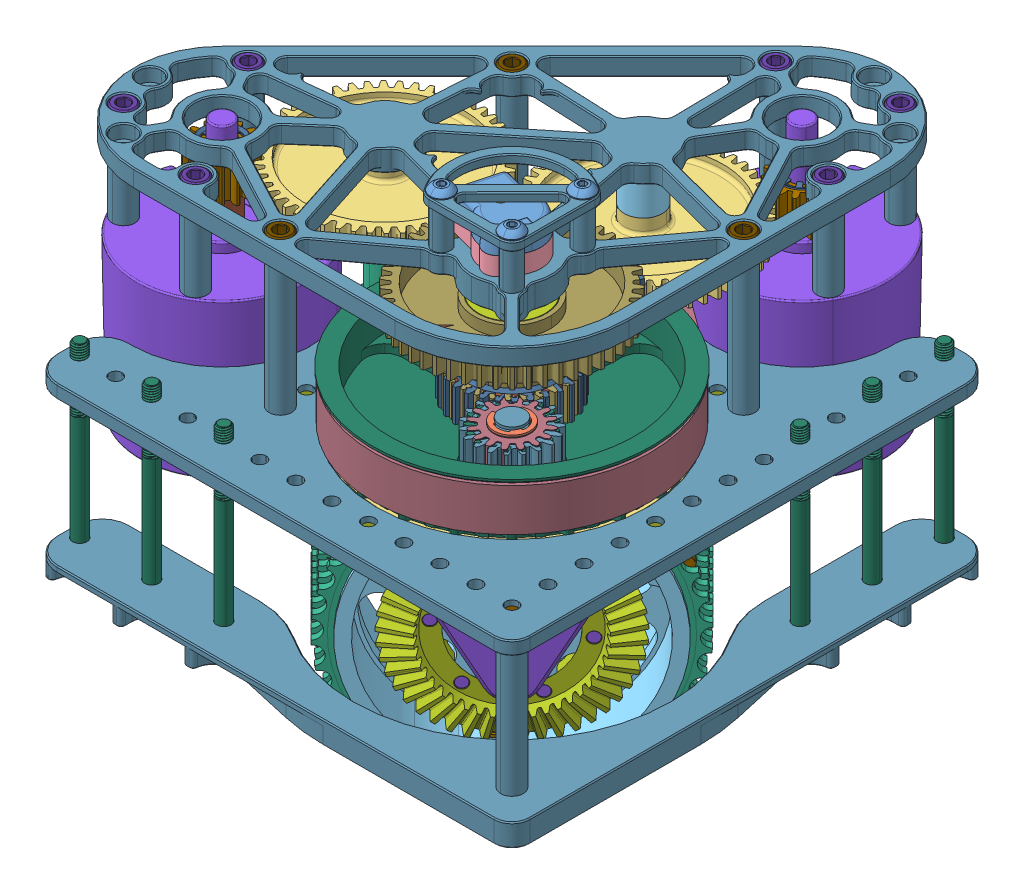
SolidWorks assembly SDS MK4i Swerve Module, 10-32, NEOs.STEP, configuration Default. Lengths in mm.
Overall size (225.17 192.31 225.17).
101 component instances, 51 part files, 0 mates.
Components (placement in the parent):
- CANcoder Assembly.STEP-1: CANcoder Assembly.STEP [Default] at (-66.675 132.3975 -66.675) x (-0.260871 0 0.965374) z (0 1 0) size (21.75 26.91 13.52)
  - CANcoder Top Housing.STEP-1: CANcoder Top Housing.STEP [Default] at origin size (21.53 26.79 8.94)
  - CANcoder PCA.STEP-1: CANcoder PCA.STEP [Default] at (0 0 22.3055) size (15.93 23.27 3.19)
  - CANcoder Screw.STEP-1: CANcoder Screw.STEP [Default] at origin size (4.24 4.24 12.65)
  - CANcoder Bottom Housing.STEP-1: CANcoder Bottom Housing.STEP [Default] at origin size (21.75 26.91 6.35)
- MK4 Turret Assembly_Billet Wheel.STEP-1: MK4 Turret Assembly_Billet Wheel.STEP [Default] at (-66.675 0 -66.675) x (-0.707107 0 0.707107) z (-0.707107 0 -0.707107) size (140.36 172.84 120.2)
  - MK4 Billet Wheel Assembly.STEP-1: MK4 Billet Wheel Assembly.STEP [Default] at (0 50.7435 0.0635) x (0 0 -1) z (-0.607274 0.794493 0) size (42.38 100.13 100.13)
    - Wheel, SDS, Nitrile Tread, 4in X 1.5in, Bearing Bore.STEP-1: Wheel, SDS, Nitrile Tread, 4in X 1.5in, Bearing Bore.STEP [Default] at origin size (42.28 88.9 88.9)
    - Tread, Blue Nitrile 4in X 1.5in.STEP-1: Tread, Blue Nitrile 4in X 1.5in.STEP [Default] at origin size (38.1 100.13 100.13)
    - Bevel Gear, 4515.STEP-1: Bevel Gear, 4515.STEP [Default] at (16.8297 0 0) x (0 -1 0) z (0 0 1) size (68.38 7.77 68.42)
    - Screw, 10-32 X .75, Button, 91255A269_91255A269.STEP-1: Screw, 10-32 X .75, Button, 91255A269_91255A269.STEP [Default] at (-4.826 0 20.6375) x (0 -0.847203 -0.531269) z (-1 0 0) size (9.17 9.17 21.62)
    - Screw, 10-32 X .75, Button, 91255A269_91255A269.STEP-2: Screw, 10-32 X .75, Button, 91255A269_91255A269.STEP [Default] at (-4.826 -17.8726 10.3187) x (0 -0.99925 -0.038711) z (-1 0 0) size (9.17 9.17 21.62)
    - Screw, 10-32 X .75, Button, 91255A269_91255A269.STEP-3: Screw, 10-32 X .75, Button, 91255A269_91255A269.STEP [Default] at (-4.826 -17.8726 -10.3187) x (0 -0.986188 -0.165633) z (-1 0 0) size (9.17 9.17 21.62)
    - Screw, 10-32 X .75, Button, 91255A269_91255A269.STEP-4: Screw, 10-32 X .75, Button, 91255A269_91255A269.STEP [Default] at (-4.826 0 -20.6375) x (0 -0.966455 -0.256836) z (-1 0 0) size (9.17 9.17 21.62)
    - Screw, 10-32 X .75, Button, 91255A269_91255A269.STEP-5: Screw, 10-32 X .75, Button, 91255A269_91255A269.STEP [Default] at (-4.826 17.8726 -10.3187) x (0 -0.95104 -0.309068) z (-1 0 0) size (9.17 9.17 21.62)
    - Screw, 10-32 X .75, Button, 91255A269_91255A269.STEP-6: Screw, 10-32 X .75, Button, 91255A269_91255A269.STEP [Default] at (-4.826 17.8726 10.3187) x (0 -0.947988 -0.318305) z (-1 0 0) size (9.17 9.17 21.62)
    - Screw, 10-32 X .5, Button, 97763A232_97763A232.STEP-1: Screw, 10-32 X .5, Button, 97763A232_97763A232.STEP [Default] at (11.1125 -40.6604 7.1695) x (-0.785325 0.107503 0.609678) z (0 -0.984808 0.173648) size (9.17 9.17 15.27)
    - Screw, 10-32 X .5, Button, 97763A232_97763A232.STEP-2: Screw, 10-32 X .5, Button, 97763A232_97763A232.STEP [Default] at (-11.1125 -40.6604 7.1695) x (-0.636812 0.133886 0.759306) z (0 -0.984808 0.173648) size (9.17 9.17 15.27)
    - Screw, 10-32 X .5, Button, 97763A232_97763A232.STEP-3: Screw, 10-32 X .5, Button, 97763A232_97763A232.STEP [Default] at (-11.1125 -40.6604 -7.1695) x (0.726076 -0.119403 0.677168) z (0 -0.984808 -0.173648) size (9.17 9.17 15.27)
    - Screw, 10-32 X .5, Button, 97763A232_97763A232.STEP-4: Screw, 10-32 X .5, Button, 97763A232_97763A232.STEP [Default] at (11.1125 -40.6604 -7.1695) x (0.841108 -0.09392 0.53265) z (0 -0.984808 -0.173648) size (9.17 9.17 15.27)
    - Screw, 10-32 X .5, Button, 97763A232_97763A232.STEP-5: Screw, 10-32 X .5, Button, 97763A232_97763A232.STEP [Default] at (-11.1125 20.6438 -35.7562) x (0.804058 -0.514897 -0.297276) z (0 0.5 -0.866025) size (9.17 9.17 15.27)
    - Screw, 10-32 X .5, Button, 97763A232_97763A232.STEP-6: Screw, 10-32 X .5, Button, 97763A232_97763A232.STEP [Default] at (11.1125 20.6438 -35.7562) x (0.926716 -0.32542 -0.187881) z (0 0.5 -0.866025) size (9.17 9.17 15.27)
    - Screw, 10-32 X .5, Button, 97763A232_97763A232.STEP-7: Screw, 10-32 X .5, Button, 97763A232_97763A232.STEP [Default] at (11.1125 20.6438 35.7562) x (0.200031 0.848523 -0.489895) z (0 0.5 0.866025) size (9.17 9.17 15.27)
    - Screw, 10-32 X .5, Button, 97763A232_97763A232.STEP-8: Screw, 10-32 X .5, Button, 97763A232_97763A232.STEP [Default] at (-11.1125 20.6438 35.7562) x (0.515054 0.74232 -0.428579) z (0 0.5 0.866025) size (9.17 9.17 15.27)
  - Double Gear, 20DP, 28T, 50T.STEP-1: Double Gear, 20DP, 28T, 50T.STEP [Default] at (0 110.1225 0) x (-0.730582 0 -0.682825) z (0 1 0) size (65.97 66.04 34.49)
  - Double Gear, 20DP, 25T, 50T.STEP-1: Double Gear, 20DP, 25T, 50T.STEP [Default] at (0 110.1225 0) x (-0.730582 0 -0.682825) z (0 1 0) size (65.97 66.04 34.49)
  - Double Gear, 20DP, 27T, 50T.STEP-1: Double Gear, 20DP, 27T, 50T.STEP [Default] at (0 110.1225 0) x (-0.730582 0 -0.682825) z (0 1 0) size (65.97 66.04 34.49)
  - Gear, 20DP, 16T, .375Hex, 217-5451.STEP-1: Gear, 20DP, 16T, .375Hex, 217-5451.STEP [Default] at (0 115.2978 -28.0162) x (-0.717682 0 -0.696371) z (0 -1 0) size (22.6 22.6 12.6)
  - Gear, 19T, 20DP, .375Hex.STEP-1: Gear, 19T, 20DP, .375Hex.STEP [Default] at (0 115.2978 -28.0162) x (-0.696371 0 0.717682) z (-0.717682 0 -0.696371) size (26.55 12.6 26.64)
  - Gear, 17T, 20DP, .375Hex.STEP-1: Gear, 17T, 20DP, .375Hex.STEP [Default] at (0 115.2978 -28.0162) x (0 1 0) z (-0.696371 0 0.717682) size (12.6 23.99 24.09)
  - Bevel Gear, 1545.STEP-1: Bevel Gear, 1545.STEP [Default] at (0 84.4935 -28.0162) x (-0.717682 0 -0.696371) z (-0.696371 0 0.717682) size (25.57 14.25 25.63)
  - Screw, .25-20 X 1 Socket, 91251A542_91251A542.STEP-1: Screw, .25-20 X 1 Socket, 91251A542_91251A542.STEP [Default] at (-20.32 101.6 30.48) x (0.982082 0 -0.188455) z (0 1 0) size (9.53 9.53 31.75)
  - Screw, .25-20 X 1 Socket, 91251A542_91251A542.STEP-2: Screw, .25-20 X 1 Socket, 91251A542_91251A542.STEP [Default] at (20.32 101.6 30.48) x (0.92897 0 -0.370156) z (0 1 0) size (9.53 9.53 31.75)
  - Screw, .25-20 X .625, 91251A539_91251A539.STEP-1: Screw, .25-20 X .625, 91251A539_91251A539.STEP [Default] at (-20.32 83.2802 -30.48) x (-0.792805 0 -0.609475) z (0 -1 0) size (9.53 9.53 22.23)
  - Screw, .25-20 X .625, 91251A539_91251A539.STEP-2: Screw, .25-20 X .625, 91251A539_91251A539.STEP [Default] at (20.32 83.2802 -30.48) x (-0.899135 0 -0.437672) z (0 -1 0) size (9.53 9.53 22.23)
  - Screw, .25-20 X .625, 91251A539_91251A539.STEP-3: Screw, .25-20 X .625, 91251A539_91251A539.STEP [Default] at (0 126.2062 0) x (-0.950706 0 -0.310093) z (0 1 0) size (9.53 9.53 22.23)
  - Screw, Shoulder, .375 X 2.5, 5_16-18, 91259A634_91259A634.STEP-1: Screw, Shoulder, .375 X 2.5, 5_16-18, 91259A634_91259A634.STEP [Default] at (0 50.7435 38.4175) x (-0.043278 -0.999063 0) z (-0.999063 0.043278 0) size (14.29 82.55 14.29)
  - E Clip, .03125, 97431A310_97431A310.STEP-1: E Clip, .03125, 97431A310_97431A310.STEP [Default] at (0 121.9153 -28.0162) x (0 -1 0) z (0.244803 0 0.969573) size (0.64 12.7 11.34)
  - Bearing, A035XPO_SA035XPO.STEP-1: Bearing, A035XPO_SA035XPO.STEP [Default] at (0 95.25 0) x (0.978935 0 0.20417) z (-0.20417 0 0.978935) size (101.6 6.35 101.6)
  - Bearing, R8ZZ.STEP-1: Bearing, R8ZZ.STEP [Default] at (0 50.7435 -12.8714) x (0.224275 -0.974526 0) z (0.974526 0.224275 0) size (28.57 7.94 28.57)
  - Bearing, R6ZZ.STEP-1: Bearing, R6ZZ.STEP [Default] at (0 50.7435 17.7514) x (0.982629 0.18558 0) z (-0.18558 0.982629 0) size (22.23 7.14 22.23)
  - Bearing, 688.STEP-1: Bearing, 688.STEP [Default] at (0 71.4775 -28.0162) x (0 -1 0) z (0 0 1) size (5 16 16)
  - Bearing, 6802.STEP-1: Bearing, 6802.STEP [Default] at (0 118.1216 0) x (0.983986 0 -0.178247) z (0.178247 0 0.983986) size (24 5 24)
  - Bearing, 6802.STEP-2: Bearing, 6802.STEP [Default] at (0 138.5216 0) x (0.983986 0 -0.178247) z (0.178247 0 0.983986) size (24 5 24)
  - Bearing, 6802.STEP-3: Bearing, 6802.STEP [Default] at (0 147.8675 0) x (0.983986 0 -0.178247) z (0.178247 0 0.983986) size (24 5 24)
  - Bearing, 6802.STEP-4: Bearing, 6802.STEP [Default] at (0 104.6675 -28.0162) x (0.928172 0 0.372151) z (-0.372151 0 0.928172) size (24 5 24)
  - Wheel Mount B Gen2.STEP-1: Wheel Mount B Gen2.STEP [Default] at (0 50.7435 -30.48) x (0 0 1) z (-1 0 0) size (15.88 49.27 57.15)
  - Wheel Mount A.STEP-1: Wheel Mount A.STEP [Default] at (0 50.7435 30.48) x (0 0 1) z (-1 0 0) size (17.09 49.74 57.15)
  - MK4 Wheel Spacer.STEP-1: MK4 Wheel Spacer.STEP [Default] at (0 50.7435 14.1796) x (0 0 1) z (-1 0 0) size (36.79 15.11 15.11)
  - Shim, 8mm ID X 14mm OD X .5mm Thick, 98055A115_98055A115.STEP-1: Shim, 8mm ID X 14mm OD X .5mm Thick, 98055A115_98055A115.STEP [Default] at (0 73.9775 -28.0162) size (14 1 14)
  - MK3 Center Column.STEP-1: MK3 Center Column.STEP [Default] at (0 113.0816 0) size (17.27 40.32 17.27)
  - magnet.STEP-1: magnet.STEP [Default] at (0 140.7033 0) size (6.35 12.7 6.35)
  - MK4 Intermediate Shaft V3.STEP-1: MK4 Intermediate Shaft V3.STEP [Default] at (0 68.3577 -28.0162) x (-0.696371 0 0.717682) z (-0.717682 0 -0.696371) size (16.51 54.51 16.51)
  - MK3 Base Pulley V3.STEP-1: MK3 Base Pulley V3.STEP [Default] at (0 98.425 0) size (98.42 27.08 98.42)
- Screw, 10-32 X .25, Button, 91255A261_91255A261.STEP-1: Screw, 10-32 X .25, Button, 91255A261_91255A261.STEP [Default] at (-42.2285 89.5096 -114.6539) x (1 0 0) z (0 -1 0) size (9.17 9.17 8.92)
- Screw, 10-32 X .25, Button, 91255A261_91255A261.STEP-2: Screw, 10-32 X .25, Button, 91255A261_91255A261.STEP [Default] at (-104.7513 89.5096 -104.7513) x (0.982082 0 -0.188455) z (0 -1 0) size (9.17 9.17 8.92)
- Screw, 10-32 X .25, Button, 91255A261_91255A261.STEP-3: Screw, 10-32 X .25, Button, 91255A261_91255A261.STEP [Default] at (-114.6539 89.5096 -42.2285) x (0.918365 0 -0.395734) z (0 -1 0) size (9.17 9.17 8.92)
- Screw, 10-32 X .25, Button, 91255A261_91255A261.STEP-4: Screw, 10-32 X .25, Button, 91255A261_91255A261.STEP [Default] at (-63.5129 89.5096 -12.9199) x (0.8 0 -0.6) z (0 -1 0) size (9.17 9.17 8.92)
- Screw, 10-32 X .25, Button, 91255A261_91255A261.STEP-5: Screw, 10-32 X .25, Button, 91255A261_91255A261.STEP [Default] at (-12.9199 89.5096 -63.5129) x (0.63358 0 -0.773678) z (0 -1 0) size (9.17 9.17 8.92)
- Screw, 10-32 X 1.5, 91251A351_91251A351.STEP-1: Screw, 10-32 X 1.5, 91251A351_91251A351.STEP [Default] at (-78.512 111.0615 -171.45) x (-0.313538 0 0.949576) z (0 -1 0) size (7.92 7.92 42.93)
- Screw, 10-32 X 2.25, 91251A354_91251A354.STEP-1: Screw, 10-32 X 2.25, 91251A354_91251A354.STEP [Default] at (-124.5154 92.0115 -124.5154) x (-0.750514 0 0.660855) z (0 -1 0) size (7.92 7.92 61.98)
- Screw, 10-32 X 2.25, 91251A354_91251A354.STEP-2: Screw, 10-32 X 2.25, 91251A354_91251A354.STEP [Default] at (-32.639 92.0115 -114.3) x (-0.612525 0 0.790452) z (0 -1 0) size (7.92 7.92 61.98)
- Screw, 10-32 X 2.25, 91251A354_91251A354.STEP-3: Screw, 10-32 X 2.25, 91251A354_91251A354.STEP [Default] at (-114.3 92.0115 -32.639) x (-0.427723 0 0.90391) z (0 -1 0) size (7.92 7.92 61.98)
- Screw, 10-32 X 2.25, 91251A354_91251A354.STEP-4: Screw, 10-32 X 2.25, 91251A354_91251A354.STEP [Default] at (-12.7 98.4885 -12.7) x (0.90391 0 -0.427723) z (0 1 0) size (7.92 7.92 61.98)
- Screw, 8-32 X .875, Button, 91255A166_91255A166.STEP-1: Screw, 8-32 X .875, Button, 91255A166_91255A166.STEP [Default] at (-80.9791 172.8661 -56.1146) x (1 0 0) z (0 1 0) size (7.92 7.92 24.45)
- Screw, 8-32 X .875, Button, 91255A166_91255A166.STEP-2: Screw, 8-32 X .875, Button, 91255A166_91255A166.STEP [Default] at (-56.1231 172.8661 -56.1146) x (0.982082 0 -0.188455) z (0 1 0) size (7.92 7.92 24.45)
- Screw, 8-32 X .875, Button, 91255A166_91255A166.STEP-3: Screw, 8-32 X .875, Button, 91255A166_91255A166.STEP [Default] at (-56.1231 172.8661 -80.9854) x (0.918365 0 -0.395734) z (0 1 0) size (7.92 7.92 24.45)
- Bearing, 688.STEP-1: Bearing, 688.STEP [Default] at (-128.0498 97.5125 -83.2602) x (0 -1 0) z (-0.444562 0 0.895748) size (5 16 16)
- Bearing, R188ZZ.STEP-1: Bearing, R188ZZ.STEP [Default] at (-77.6314 97.6313 -123.9376) x (-0.188457 0 -0.982081) z (0.982081 0 -0.188457) size (12.7 4.76 12.7)
- Bearing, 688.STEP-2: Bearing, 688.STEP [Default] at (-77.6314 150.1375 -123.9376) x (0 -1 0) z (-0.336154 0 0.941807) size (5 16 16)
- Bearing, 688.STEP-3: Bearing, 688.STEP [Default] at (-128.0498 148.8167 -83.2602) x (0 -1 0) z (-0.336154 0 0.941807) size (5 16 16)
- Gear, 50T, 20DP, .375Hex.STEP-1: Gear, 50T, 20DP, .375Hex.STEP [Default] at (-128.0498 139.8651 -83.2602) x (0.985885 0 -0.167422) z (0 1 0) size (65.97 66.04 12.65)
- Gear, 50T, 20DP, .375Hex.STEP-2: Gear, 50T, 20DP, .375Hex.STEP [Default] at (-77.6314 128.4859 -123.9376) x (-0.963721 0 0.266911) z (0 1 0) size (65.97 66.04 12.65)
- MK4i Steering Shaft Tall.STEP-1: MK4i Steering Shaft Tall.STEP [Default] at (-77.6314 152.5105 -123.9376) x (0.998641 0 -0.05212) z (0.05212 0 0.998641) size (17.78 57.04 17.78)
- MK4i Steering Shaft Spacer.STEP-1: MK4i Steering Shaft Spacer.STEP [Default] at (-77.6314 134.8105 -123.9376) x (-0.728275 0 -0.685285) z (0.685285 0 -0.728275) size (13.36 12.7 13.36)
- MK4i Shaft, Drive Idler.STEP-1: MK4i Shaft, Drive Idler.STEP [Default] at (-128.0498 100.0125 -83.2602) size (13.36 56.18 13.36)
- Screw, 3-48 X .1875, Pan Phillips, 90272A091_90272A091.STEP-1: Screw, 3-48 X .1875, Pan Phillips, 90272A091_90272A091.STEP [Default] at (-68.5859 150.495 -73.8677) x (1 0 0) z (0 1 0) size (4.9 4.9 6.49)
- Screw, 3-48 X .1875, Pan Phillips, 90272A091_90272A091.STEP-2: Screw, 3-48 X .1875, Pan Phillips, 90272A091_90272A091.STEP [Default] at (-64.7641 150.495 -59.4823) x (0.911631 0 -0.411009) z (0 1 0) size (4.9 4.9 6.49)
- Motor, NEO.STEP-1: Motor, NEO.STEP [Default] at (-158.75 119.0625 -56.515) x (0.866025 0 -0.5) z (0 1 0) size (59.98 59.98 90)
- Motor, NEO.STEP-2: Motor, NEO.STEP [Default] at (-56.515 119.0625 -158.75) x (0.866025 0 0.5) z (0 1 0) size (59.98 59.98 90)
- Shim, 8mm ID X 14mm OD X .5mm Thick, 98055A115_98055A115.STEP-1: Shim, 8mm ID X 14mm OD X .5mm Thick, 98055A115_98055A115.STEP [Default] at (-56.515 122.5625 -158.75) x (0.942304 0 -0.334759) z (0.334759 0 0.942304) size (14 1 14)
- Gear, 20DP, 14T, 8mm REV1.STEP-1: Gear, 20DP, 14T, 8mm REV1.STEP [Default] at (-56.515 123.5625 -158.75) x (0 1 0) z (-0.866025 0 -0.5) size (12.7 19.97 20.32)
- Retaining Ring, 8mm, 98430A132_98430A132.STEP-1: Retaining Ring, 8mm, 98430A132_98430A132.STEP [Default] at (-56.515 136.2625 -158.75) x (0 1 0) z (-0.12503 0 0.992153) size (1.07 14.83 14.83)
- Gear, 20DP, 14T, 8mm REV1.STEP-2: Gear, 20DP, 14T, 8mm REV1.STEP [Default] at (-158.75 133.675 -56.515) x (0 1 0) z (-0.866025 0 0.5) size (12.7 19.97 20.32)
- Spacer, 8mmID X .437 OD X 0.437 L.STEP-1: Spacer, 8mmID X .437 OD X 0.437 L.STEP [Default] at (-158.75 122.5625 -56.515) size (11.11 11.11 11.11)
- Retaining Ring, 8mm, 98430A132_98430A132.STEP-2: Retaining Ring, 8mm, 98430A132_98430A132.STEP [Default] at (-158.75 146.375 -56.515) x (0 1 0) z (0.064186 0 0.997938) size (1.07 14.83 14.83)
- Machine Key, 2 X 2 X 12mm.STEP-1: Machine Key, 2 X 2 X 12mm.STEP [Default] at (-160.675 140.025 -59.8492) x (-0.866025 0 0.5) z (-0.5 0 -0.866025) size (2 12 2)
- Machine Key, 2 X 2 X 12mm.STEP-2: Machine Key, 2 X 2 X 12mm.STEP [Default] at (-54.59 129.9125 -162.0842) x (0.866025 0 0.5) z (-0.5 0 0.866025) size (2 12 2)
- Belt, 320-5M-15.STEP-1: Belt, 320-5M-15.STEP [Default] at (-66.675 109.6038 -66.675) x (0.982183 0 -0.187927) z (0.187927 0 0.982183) size (97.78 15 116.29)
- Screw, 10-32 X 1.5, 91251A351_91251A351.STEP-2: Screw, 10-32 X 1.5, 91251A351_91251A351.STEP [Default] at (-43.815 111.0615 -180.747) x (0.087837 0 0.996135) z (0 -1 0) size (7.92 7.92 42.93)
- Screw, 10-32 X 1.5, 91251A351_91251A351.STEP-3: Screw, 10-32 X 1.5, 91251A351_91251A351.STEP [Default] at (-34.518 111.0615 -146.05) x (0.536014 0 0.844209) z (0 -1 0) size (7.92 7.92 42.93)
- Screw, 10-32 X 1.5, 91251A351_91251A351.STEP-4: Screw, 10-32 X 1.5, 91251A351_91251A351.STEP [Default] at (-146.05 111.0615 -34.518) x (0.711925 0 0.702256) z (0 -1 0) size (7.92 7.92 42.93)
- Screw, 10-32 X 1.5, 91251A351_91251A351.STEP-5: Screw, 10-32 X 1.5, 91251A351_91251A351.STEP [Default] at (-180.747 111.0615 -43.815) x (0.905013 0 0.425384) z (0 -1 0) size (7.92 7.92 42.93)
- Screw, 10-32 X 1.5, 91251A351_91251A351.STEP-6: Screw, 10-32 X 1.5, 91251A351_91251A351.STEP [Default] at (-171.45 111.0615 -78.512) x (0.949576 0 0.313538) z (0 -1 0) size (7.92 7.92 42.93)
- MK4i Master Part V2_NEO Config.STEP-1: MK4i Master Part V2_NEO Config.STEP [Default] at origin size (189.87 134.14 189.87)
- Screw, 10-32 X 2.5, 91251A355_91251A355.STEP-1: Screw, 10-32 X 2.5, 91251A355_91251A355.STEP [Default] at (-114.3 104.8385 -12.7) x (-0.837169 0 -0.546944) z (0 1 0) size (7.92 7.92 68.33)
- Screw, 10-32 X 2.5, 91251A355_91251A355.STEP-2: Screw, 10-32 X 2.5, 91251A355_91251A355.STEP [Default] at (-139.7 104.8385 -12.7) x (-0.925243 0 -0.379375) z (0 1 0) size (7.92 7.92 68.33)
- Screw, 10-32 X 2.5, 91251A355_91251A355.STEP-3: Screw, 10-32 X 2.5, 91251A355_91251A355.STEP [Default] at (-12.7 104.8385 -114.3) x (-0.985271 0 -0.170998) z (0 1 0) size (7.92 7.92 68.33)
- Screw, 10-32 X 2.5, 91251A355_91251A355.STEP-4: Screw, 10-32 X 2.5, 91251A355_91251A355.STEP [Default] at (-12.7 104.8385 -139.7) x (-0.997902 0 0.064746) z (0 1 0) size (7.92 7.92 68.33)
- Screw, 10-32 X 2.5, 91251A355_91251A355.STEP-5: Screw, 10-32 X 2.5, 91251A355_91251A355.STEP [Default] at (-12.7 104.8385 -165.1) x (-0.953572 0 0.301166) z (0 1 0) size (7.92 7.92 68.33)
- Screw, 10-32 X 2.5, 91251A355_91251A355.STEP-6: Screw, 10-32 X 2.5, 91251A355_91251A355.STEP [Default] at (-165.1 104.8385 -12.7) x (-0.980159 0 -0.198211) z (0 1 0) size (7.92 7.92 68.33)
